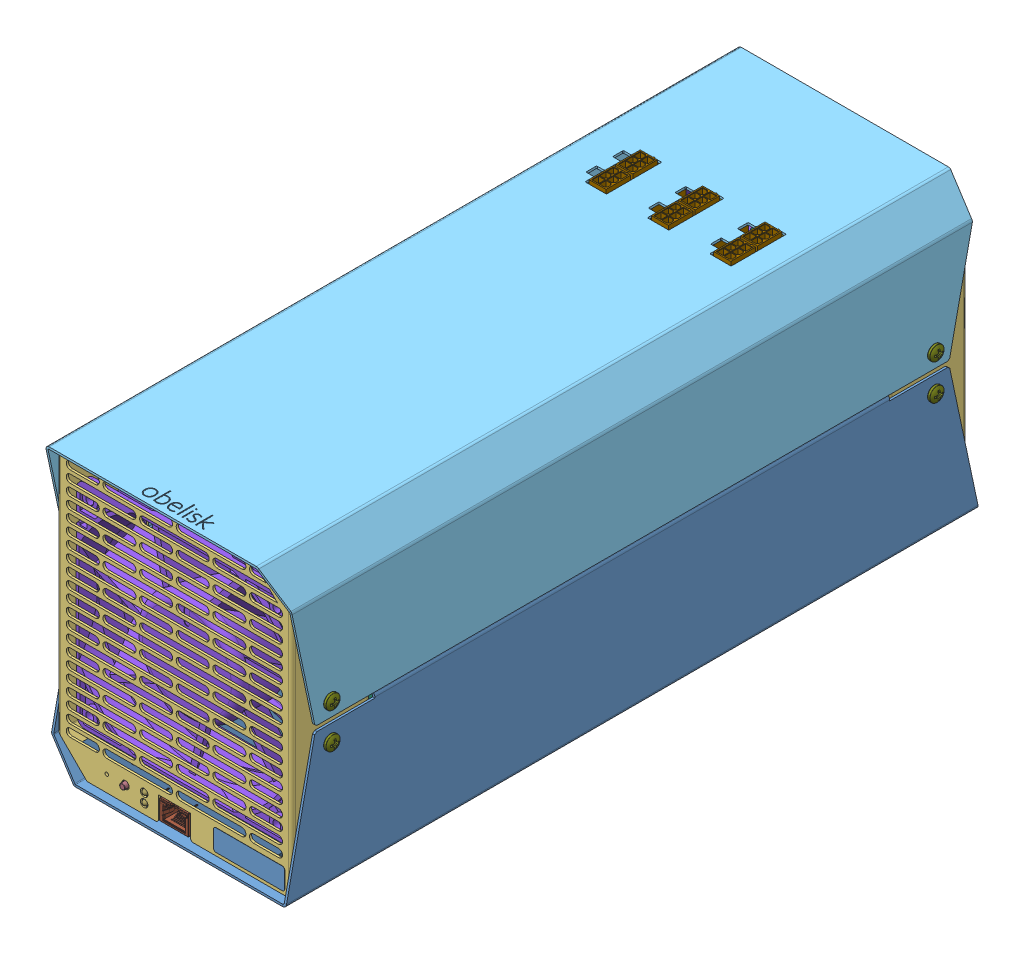
SolidWorks assembly TE-1719_742921-02_SC1-Assem_PRELIM, configuration Captive Nut Fasteners. Lengths in mm.
Overall size (140.99 162.11 388.48).
170 component instances, 20 part files, 45 mates.
Components (placement in the parent):
- TE-1719_SC1-LAYOUT_v03-1: TE-1719_SC1-LAYOUT_v03 [Default] at origin
- TE-1719_742931-04_SC1-Sheet-Metal-Subassem-1: TE-1719_742931-04_SC1-Sheet-Metal-Subassem [Default] at (0 0 5) size (135 156.2 388.48)
  - TE-1719_742923-02_SC1-Base-1: TE-1719_742923-02_SC1-Base [Default] at origin size (135 91 388.48)
    - TE-1719_742923-02_SC1-Base-1: TE-1719_742923-02_SC1-Base [Default] at origin size (135 91 388.48)
    - PEM-Standoff_BSO-440-18ZI-1: PEM-Standoff_BSO-440-18ZI [Default] at (31.1 0.475 -65) x (0 -1 0) z (0 0 1) size (14.27 4.75 5.48)
    - PEM-Standoff_BSO-440-18ZI-2: PEM-Standoff_BSO-440-18ZI [Default] at (31.1 0.475 -249.5) x (0 -1 0) z (0 0 1) size (14.27 4.75 5.48)
    - PEM-Standoff_BSO-440-18ZI-3: PEM-Standoff_BSO-440-18ZI [Default] at (31.1 0.475 -313.5) x (0 -1 0) z (0 0 1) size (14.27 4.75 5.48)
    - PEM-Standoff_BSO-440-18ZI-4: PEM-Standoff_BSO-440-18ZI [Default] at (-3.9 0.475 -313.5) x (0 -1 0) z (0 0 1) size (14.27 4.75 5.48)
    - PEM-Standoff_BSO-440-18ZI-5: PEM-Standoff_BSO-440-18ZI [Default] at (-38.9 0.475 -313.5) x (0 -1 0) z (0 0 1) size (14.27 4.75 5.48)
    - PEM-Standoff_BSO-440-18ZI-6: PEM-Standoff_BSO-440-18ZI [Default] at (-38.9 0.475 -249.5) x (0 -1 0) z (0 0 1) size (14.27 4.75 5.48)
    - PEM-Standoff_BSO-440-18ZI-7: PEM-Standoff_BSO-440-18ZI [Default] at (-3.9 0.475 -249.5) x (0 -1 0) z (0 0 1) size (14.27 4.75 5.48)
    - PEM-Standoff_BSO-440-18ZI-8: PEM-Standoff_BSO-440-18ZI [Default] at (-38.9 0.475 -65) x (0 -1 0) z (0 0 1) size (14.27 4.75 5.48)
  - TE-1719_742926-04_SC1-Front-Grill-1: TE-1719_742926-04_SC1-Front-Grill [Default] at (0 0 -5) size (132 155 55.8)
    - TE-1719_742926-04_742928-04_MASTER-MODEL_SC1-FRONT-REAR-1: TE-1719_742926-04_742928-04_MASTER-MODEL_SC1-FRONT-REAR [Front_PEM-Nuts] at origin size (132 155 55.8)
    - PEM-Nut_S-M4-1ZI-1: PEM-Nut_S-M4-1ZI [Default] at (65.7508 89 -20) x (-1 0 0) z (0 0 -1) size (2.97 7.87 7.87)
    - PEM-Nut_S-M4-1ZI-2: PEM-Nut_S-M4-1ZI [Default] at (65.7508 69 -20) x (-1 0 0) z (0 0 -1) size (2.97 7.87 7.87)
    - PEM-Nut_S-M4-1ZI-3: PEM-Nut_S-M4-1ZI [Default] at (51 1.4492 -20) x (0 1 0) z (-1 0 0) size (2.97 7.87 7.87)
    - PEM-Nut_S-M4-1ZI-8: PEM-Nut_S-M4-1ZI [Default] at (-65.7508 89 -20) size (2.97 7.87 7.87)
    - PEM-Nut_S-M4-1ZI-9: PEM-Nut_S-M4-1ZI [Default] at (-65.7508 69 -20) size (2.97 7.87 7.87)
    - PEM-Nut_S-M4-1ZI-7: PEM-Nut_S-M4-1ZI [Default] at (-35 1.4492 -20) x (0 1 0) z (-1 0 0) size (2.97 7.87 7.87)
  - TE-1719_742928-04_SC1-Rear-Grill-1: TE-1719_742928-04_SC1-Rear-Grill [Default] at (0 0 -384) x (-1 0 0) z (0 0 -1) size (132 155 55.8)
    - TE-1719_742926-04_742928-04_MASTER-MODEL_SC1-FRONT-REAR-1: TE-1719_742926-04_742928-04_MASTER-MODEL_SC1-FRONT-REAR [Rear_PEM-Nuts] at origin size (132 155 55.8)
    - PEM-Nut_S-M4-1ZI-1: PEM-Nut_S-M4-1ZI [Default] at (65.7508 89 -20) x (-1 0 0) z (0 0 -1) size (2.97 7.87 7.87)
    - PEM-Nut_S-M4-1ZI-2: PEM-Nut_S-M4-1ZI [Default] at (65.7508 69 -20) x (-1 0 0) z (0 0 -1) size (2.97 7.87 7.87)
    - PEM-Nut_S-M4-1ZI-3: PEM-Nut_S-M4-1ZI [Default] at (35 1.4492 -20) x (0 1 0) z (-1 0 0) size (2.97 7.87 7.87)
    - PEM-Nut_S-M4-1ZI-9: PEM-Nut_S-M4-1ZI [Default] at (-65.7508 89 -20) size (2.97 7.87 7.87)
    - PEM-Nut_S-M4-1ZI-10: PEM-Nut_S-M4-1ZI [Default] at (-65.7508 69 -20) size (2.97 7.87 7.87)
    - PEM-Nut_S-M4-1ZI-8: PEM-Nut_S-M4-1ZI [Default] at (-51 1.4492 -20) x (0 1 0) z (-1 0 0) size (2.97 7.87 7.87)
  - TE-1719_742924-02_SC1-Cover-1: TE-1719_742924-02_SC1-Cover [Stamped] at origin size (135 77.69 388.48)
  - TE-1719_742933-00_SC1-AIRFLOW-GUIDE-1: TE-1719_742933-00_SC1-AIRFLOW-GUIDE [Default] at (52.5 81 -49.2192) size (53.8 124 20.2)
  - TE-1719_742933-00_SC1-AIRFLOW-GUIDE-2: TE-1719_742933-00_SC1-AIRFLOW-GUIDE [Default] at (52.5 81 -339.7808) x (1 0 0) z (0 0 -1) size (53.8 124 20.2)
- TE-1719_742929-01_SC1-Upper-Guide-1: TE-1719_742929-01_SC1-Upper-Guide [Default] at (0 148 -44.2192) size (114 1.59 21.5)
- FAN_Jaro_JCD1203812LBBA0D(4600)-3: FAN_Jaro_JCD1203812LBBA0D(4600) [Default] at (0 81 -43) x (-1 0 0) z (0 1 0) size (120.5 45.48 120.5)
- SIAHashBd742901R0pcb_03-26-18-1: SIAHashBd742901R0pcb_03-26-18 [Default] at (-31.3 17.4875 -316.5) x (0 0 1) z (-1 0 0) size (258 156.75 30.01)
- PCB_Main-Control-Board_REF-02-1: PCB_Main-Control-Board_REF-02 [Default] at origin size (110 11.6 320)
- M-RJE73-188-00XX0-REVG1-1: M-RJE73-188-00XX0-REVG1 [Default] at (0 8.4625 -10.56) x (-1 0 0) z (0 0 1) size (16.14 13.57 15.3)
- LED_Dual-3mm_Dialight-1: LED_Dual-3mm_Dialight [Default] at (-17 14.2875 -2.2192) x (0 0 -1) z (-1 0 0) size (11 13.64 4.32)
- EVQPF008K-1: EVQPF008K [Default] at (-27.5 10.2875 -4.2192) x (-1 0 0) z (0 0 1) size (8.58 10.9 12.35)
- EVQPF008K-2: EVQPF008K [Default] at (-38 10.2875 -7.7192) x (-1 0 0) z (0 0 1) size (8.58 10.9 12.35)
- SCREW_4-40x250_SEMS-SCREW_90402A106-1: SCREW_4-40x250_SEMS-SCREW_90402A106 [90402A106] at (31.0998 10.1058 -60) x (1 0 0) z (0 1 0) size (5.84 5.84 8.52)
- SCREW_10-14X750_THREAD-FORM_99461A460-1: SCREW_10-14X750_THREAD-FORM_99461A460 [99461A460] at (52.5 133.5 -34.6942) x (-0.923728 -0.383049 0) z (0 0 -1) size (9.47 9.47 23.08)
- SCREW_M4X6_NYLON-PATCH_BLACK_95911A254-26: SCREW_M4X6_NYLON-PATCH_BLACK_95911A254 [95911A254] at (61.5 89 -20) x (0 0 -1) z (-1 0 0) size (8 8 9.2)
- SCREW_M4X6_NYLON-PATCH_BLACK_95911A254-27: SCREW_M4X6_NYLON-PATCH_BLACK_95911A254 [95911A254] at (51 6 -20) x (1 0 0) z (0 1 0) size (8 8 9.2)
- SCREW_M4X6_NYLON-PATCH_BLACK_95911A254-28: SCREW_M4X6_NYLON-PATCH_BLACK_95911A254 [95911A254] at (61.5 69 -20) x (0 0 1) z (-1 0 0) size (8 8 9.2)
- SCREW_M4X6_NYLON-PATCH_BLACK_95911A254-29: SCREW_M4X6_NYLON-PATCH_BLACK_95911A254 [95911A254] at (61.5 69 -359) x (0 0 1) z (-1 0 0) size (8 8 9.2)
- SCREW_M4X6_NYLON-PATCH_BLACK_95911A254-30: SCREW_M4X6_NYLON-PATCH_BLACK_95911A254 [95911A254] at (61.5 89 -359) x (0 0 -1) z (-1 0 0) size (8 8 9.2)
- SCREW_M4X6_NYLON-PATCH_BLACK_95911A254-31: SCREW_M4X6_NYLON-PATCH_BLACK_95911A254 [95911A254] at (-61.5 69 -20) x (0 0 -1) z (1 0 0) size (8 8 9.2)
- SCREW_M4X6_NYLON-PATCH_BLACK_95911A254-32: SCREW_M4X6_NYLON-PATCH_BLACK_95911A254 [95911A254] at (-61.5 89 -20) x (0 0 1) z (1 0 0) size (8 8 9.2)
- SCREW_M4X6_NYLON-PATCH_BLACK_95911A254-33: SCREW_M4X6_NYLON-PATCH_BLACK_95911A254 [95911A254] at (-61.5 69 -359) x (0 0 -1) z (1 0 0) size (8 8 9.2)
- SCREW_M4X6_NYLON-PATCH_BLACK_95911A254-34: SCREW_M4X6_NYLON-PATCH_BLACK_95911A254 [95911A254] at (-61.5 89 -359) x (0 0 1) z (1 0 0) size (8 8 9.2)
- SCREW_10-14X750_THREAD-FORM_99461A460-9: SCREW_10-14X750_THREAD-FORM_99461A460 [99461A460] at (-52.5 133.5 -34.6942) x (0.923728 -0.383049 0) z (0 0 -1) size (9.47 9.47 23.08)
- SCREW_4-40x250_SEMS-SCREW_90402A106-2: SCREW_4-40x250_SEMS-SCREW_90402A106 [90402A106] at (31.0998 10.1058 -244.5) x (1 0 0) z (0 1 0) size (5.84 5.84 8.52)
- SCREW_4-40x250_SEMS-SCREW_90402A106-3: SCREW_4-40x250_SEMS-SCREW_90402A106 [90402A106] at (31.0998 10.1058 -308.5) x (1 0 0) z (0 1 0) size (5.84 5.84 8.52)
- SCREW_4-40x250_SEMS-SCREW_90402A106-4: SCREW_4-40x250_SEMS-SCREW_90402A106 [90402A106] at (-38.9002 10.1058 -60) x (1 0 0) z (0 1 0) size (5.84 5.84 8.52)
- SCREW_4-40x250_SEMS-SCREW_90402A106-5: SCREW_4-40x250_SEMS-SCREW_90402A106 [90402A106] at (-3.9002 10.1058 -244.5) x (1 0 0) z (0 1 0) size (5.84 5.84 8.52)
- SCREW_4-40x250_SEMS-SCREW_90402A106-6: SCREW_4-40x250_SEMS-SCREW_90402A106 [90402A106] at (-38.9002 10.1058 -244.5) x (1 0 0) z (0 1 0) size (5.84 5.84 8.52)
- SCREW_4-40x250_SEMS-SCREW_90402A106-7: SCREW_4-40x250_SEMS-SCREW_90402A106 [90402A106] at (-38.9002 10.1058 -308.5) x (1 0 0) z (0 1 0) size (5.84 5.84 8.52)
- SCREW_4-40x250_SEMS-SCREW_90402A106-8: SCREW_4-40x250_SEMS-SCREW_90402A106 [90402A106] at (-3.9002 10.1058 -308.5) x (1 0 0) z (0 1 0) size (5.84 5.84 8.52)
- SCREW_10-14X750_THREAD-FORM_99461A460-10: SCREW_10-14X750_THREAD-FORM_99461A460 [99461A460] at (52.5 28.5 -34.6942) x (0.923728 -0.383049 0) z (0 0 -1) size (9.47 9.47 23.08)
- SCREW_10-14X750_THREAD-FORM_99461A460-11: SCREW_10-14X750_THREAD-FORM_99461A460 [99461A460] at (-52.5 28.5 -34.6942) x (-0.923728 -0.383049 0) z (0 0 -1) size (9.47 9.47 23.08)
- FAN_Jaro_JCD1203812LBBA0D(4600)-4: FAN_Jaro_JCD1203812LBBA0D(4600) [Default] at (0 81 -375.9987) x (-1 0 0) z (0 1 0) size (120.5 45.48 120.5)
- SCREW_10-14X750_THREAD-FORM_99461A460-12: SCREW_10-14X750_THREAD-FORM_99461A460 [99461A460] at (52.5 133.5 -344.3058) x (0.923728 0.383049 0) z (0 0 1) size (9.47 9.47 23.08)
- SCREW_10-14X750_THREAD-FORM_99461A460-13: SCREW_10-14X750_THREAD-FORM_99461A460 [99461A460] at (-52.5 133.5 -344.3058) x (-0.923728 0.383049 0) z (0 0 1) size (9.47 9.47 23.08)
- SCREW_10-14X750_THREAD-FORM_99461A460-14: SCREW_10-14X750_THREAD-FORM_99461A460 [99461A460] at (52.5 28.5 -344.3058) x (-0.923728 0.383049 0) z (0 0 1) size (9.47 9.47 23.08)
- SCREW_10-14X750_THREAD-FORM_99461A460-15: SCREW_10-14X750_THREAD-FORM_99461A460 [99461A460] at (-52.5 28.5 -344.3058) x (0.923728 0.383049 0) z (0 0 1) size (9.47 9.47 23.08)
- SCREW_M4X6_NYLON-PATCH_BLACK_95911A254-35: SCREW_M4X6_NYLON-PATCH_BLACK_95911A254 [95911A254] at (51 6 -359) x (1 0 0) z (0 1 0) size (8 8 9.2)
- SCREW_M4X6_NYLON-PATCH_BLACK_95911A254-36: SCREW_M4X6_NYLON-PATCH_BLACK_95911A254 [95911A254] at (-35 6 -20) x (-1 0 0) z (0 1 0) size (8 8 9.2)
- SCREW_M4X6_NYLON-PATCH_BLACK_95911A254-37: SCREW_M4X6_NYLON-PATCH_BLACK_95911A254 [95911A254] at (-35 6 -359) x (-1 0 0) z (0 1 0) size (8 8 9.2)
- SIAHashBd742901R0pcb_03-26-18-4: SIAHashBd742901R0pcb_03-26-18 [Default] at (3.7 17.4875 -316.5) x (0 0 1) z (-1 0 0) size (258 156.75 30.01)
- SIAHashBd742901R0pcb_03-26-18-5: SIAHashBd742901R0pcb_03-26-18 [Default] at (38.7 17.4875 -316.5) x (0 0 1) z (-1 0 0) size (258 156.75 30.01)
- TE-1719_742929-01_SC1-Upper-Guide-3: TE-1719_742929-01_SC1-Upper-Guide [Default] at (0 149.5875 -334.7808) x (1 0 0) z (0 0 -1) size (114 1.59 21.5)
- RIVET_3-32_97447A110-1: RIVET_3-32_97447A110 [Default] at (37 149.5875 -50.2192) size (5.03 10.34 5.03)
- RIVET_3-32_97447A110-2: RIVET_3-32_97447A110 [Default] at (37 149.5875 -328.7808) size (5.03 10.34 5.03)
- RIVET_3-32_97447A110-3: RIVET_3-32_97447A110 [Default] at (-37 149.5875 -50.2192) x (-1 0 0) z (0 0 -1) size (5.03 10.34 5.03)
- RIVET_3-32_97447A110-4: RIVET_3-32_97447A110 [Default] at (-37 149.5875 -328.7808) x (-1 0 0) z (0 0 -1) size (5.03 10.34 5.03)
- RIVET-WASHER_3-32_90183A308-1: RIVET-WASHER_3-32_90183A308 [90183A308] at (37 146.7808 -50.2192) x (-0.837169 0 -0.546944) z (0 1 0) size (7.92 7.92 1.73)
- RIVET-WASHER_3-32_90183A308-2: RIVET-WASHER_3-32_90183A308 [90183A308] at (37 145.0536 -328.7808) x (-0.837169 0 0.546944) z (0 -1 0) size (7.92 7.92 1.73)
- RIVET-WASHER_3-32_90183A308-3: RIVET-WASHER_3-32_90183A308 [90183A308] at (-37 145.0536 -50.2192) x (0.837169 0 -0.546944) z (0 -1 0) size (7.92 7.92 1.73)
- RIVET-WASHER_3-32_90183A308-4: RIVET-WASHER_3-32_90183A308 [90183A308] at (-37 146.7808 -328.7808) x (0.837169 0 0.546944) z (0 1 0) size (7.92 7.92 1.73)
- TE-1719_742931-04_SC1-Sheet-Metal-Subassem-2: TE-1719_742931-04_SC1-Sheet-Metal-Subassem [Default] at (150 0 5) size (135 156.2 388.48) (suppressed, hidden)
  - TE-1719_742923-02_SC1-Base-1: TE-1719_742923-02_SC1-Base [Default] at origin size (135 91 388.48)
    - TE-1719_742923-02_SC1-Base-1: TE-1719_742923-02_SC1-Base [Default] at origin size (135 91 388.48)
    - PEM-Standoff_BSO-440-18ZI-1: PEM-Standoff_BSO-440-18ZI [Default] at (31.1 0.475 -65) x (0 -1 0) z (0 0 1) size (14.27 4.75 5.48)
    - PEM-Standoff_BSO-440-18ZI-2: PEM-Standoff_BSO-440-18ZI [Default] at (31.1 0.475 -249.5) x (0 -1 0) z (0 0 1) size (14.27 4.75 5.48)
    - PEM-Standoff_BSO-440-18ZI-3: PEM-Standoff_BSO-440-18ZI [Default] at (31.1 0.475 -313.5) x (0 -1 0) z (0 0 1) size (14.27 4.75 5.48)
    - PEM-Standoff_BSO-440-18ZI-4: PEM-Standoff_BSO-440-18ZI [Default] at (-3.9 0.475 -313.5) x (0 -1 0) z (0 0 1) size (14.27 4.75 5.48)
    - PEM-Standoff_BSO-440-18ZI-5: PEM-Standoff_BSO-440-18ZI [Default] at (-38.9 0.475 -313.5) x (0 -1 0) z (0 0 1) size (14.27 4.75 5.48)
    - PEM-Standoff_BSO-440-18ZI-6: PEM-Standoff_BSO-440-18ZI [Default] at (-38.9 0.475 -249.5) x (0 -1 0) z (0 0 1) size (14.27 4.75 5.48)
    - PEM-Standoff_BSO-440-18ZI-7: PEM-Standoff_BSO-440-18ZI [Default] at (-3.9 0.475 -249.5) x (0 -1 0) z (0 0 1) size (14.27 4.75 5.48)
    - PEM-Standoff_BSO-440-18ZI-8: PEM-Standoff_BSO-440-18ZI [Default] at (-38.9 0.475 -65) x (0 -1 0) z (0 0 1) size (14.27 4.75 5.48)
  - TE-1719_742926-04_SC1-Front-Grill-1: TE-1719_742926-04_SC1-Front-Grill [Default] at (0 0 -5) size (132 155 55.8)
    - TE-1719_742926-04_742928-04_MASTER-MODEL_SC1-FRONT-REAR-1: TE-1719_742926-04_742928-04_MASTER-MODEL_SC1-FRONT-REAR [Front_PEM-Nuts] at origin size (132 155 55.8)
    - PEM-Nut_S-M4-1ZI-1: PEM-Nut_S-M4-1ZI [Default] at (65.7508 89 -20) x (-1 0 0) z (0 0 -1) size (2.97 7.87 7.87)
    - PEM-Nut_S-M4-1ZI-2: PEM-Nut_S-M4-1ZI [Default] at (65.7508 69 -20) x (-1 0 0) z (0 0 -1) size (2.97 7.87 7.87)
    - PEM-Nut_S-M4-1ZI-3: PEM-Nut_S-M4-1ZI [Default] at (51 1.4492 -20) x (0 1 0) z (-1 0 0) size (2.97 7.87 7.87)
    - PEM-Nut_S-M4-1ZI-8: PEM-Nut_S-M4-1ZI [Default] at (-65.7508 89 -20) size (2.97 7.87 7.87)
    - PEM-Nut_S-M4-1ZI-9: PEM-Nut_S-M4-1ZI [Default] at (-65.7508 69 -20) size (2.97 7.87 7.87)
    - PEM-Nut_S-M4-1ZI-7: PEM-Nut_S-M4-1ZI [Default] at (-35 1.4492 -20) x (0 1 0) z (-1 0 0) size (2.97 7.87 7.87)
  - TE-1719_742928-04_SC1-Rear-Grill-1: TE-1719_742928-04_SC1-Rear-Grill [Default] at (0 0 -384) x (-1 0 0) z (0 0 -1) size (132 155 55.8)
    - TE-1719_742926-04_742928-04_MASTER-MODEL_SC1-FRONT-REAR-1: TE-1719_742926-04_742928-04_MASTER-MODEL_SC1-FRONT-REAR [Rear_PEM-Nuts] at origin size (132 155 55.8)
    - PEM-Nut_S-M4-1ZI-1: PEM-Nut_S-M4-1ZI [Default] at (65.7508 89 -20) x (-1 0 0) z (0 0 -1) size (2.97 7.87 7.87)
    - PEM-Nut_S-M4-1ZI-2: PEM-Nut_S-M4-1ZI [Default] at (65.7508 69 -20) x (-1 0 0) z (0 0 -1) size (2.97 7.87 7.87)
    - PEM-Nut_S-M4-1ZI-3: PEM-Nut_S-M4-1ZI [Default] at (35 1.4492 -20) x (0 1 0) z (-1 0 0) size (2.97 7.87 7.87)
    - PEM-Nut_S-M4-1ZI-9: PEM-Nut_S-M4-1ZI [Default] at (-65.7508 89 -20) size (2.97 7.87 7.87)
    - PEM-Nut_S-M4-1ZI-10: PEM-Nut_S-M4-1ZI [Default] at (-65.7508 69 -20) size (2.97 7.87 7.87)
    - PEM-Nut_S-M4-1ZI-8: PEM-Nut_S-M4-1ZI [Default] at (-51 1.4492 -20) x (0 1 0) z (-1 0 0) size (2.97 7.87 7.87)
  - TE-1719_742924-02_SC1-Cover-1: TE-1719_742924-02_SC1-Cover [Stamped] at origin size (135 77.69 388.48)
  - TE-1719_742933-00_SC1-AIRFLOW-GUIDE-1: TE-1719_742933-00_SC1-AIRFLOW-GUIDE [Default] at (52.5 81 -49.2192) size (53.8 124 20.2)
  - TE-1719_742933-00_SC1-AIRFLOW-GUIDE-2: TE-1719_742933-00_SC1-AIRFLOW-GUIDE [Default] at (52.5 81 -339.7808) x (1 0 0) z (0 0 -1) size (53.8 124 20.2)
- TE-1719_742931-04_SC1-Sheet-Metal-Subassem-3: TE-1719_742931-04_SC1-Sheet-Metal-Subassem [Default] at (300 0 5) size (135 156.2 388.48) (suppressed, hidden)
  - TE-1719_742923-02_SC1-Base-1: TE-1719_742923-02_SC1-Base [Default] at origin size (135 91 388.48)
    - TE-1719_742923-02_SC1-Base-1: TE-1719_742923-02_SC1-Base [Default] at origin size (135 91 388.48)
    - PEM-Standoff_BSO-440-18ZI-1: PEM-Standoff_BSO-440-18ZI [Default] at (31.1 0.475 -65) x (0 -1 0) z (0 0 1) size (14.27 4.75 5.48)
    - PEM-Standoff_BSO-440-18ZI-2: PEM-Standoff_BSO-440-18ZI [Default] at (31.1 0.475 -249.5) x (0 -1 0) z (0 0 1) size (14.27 4.75 5.48)
    - PEM-Standoff_BSO-440-18ZI-3: PEM-Standoff_BSO-440-18ZI [Default] at (31.1 0.475 -313.5) x (0 -1 0) z (0 0 1) size (14.27 4.75 5.48)
    - PEM-Standoff_BSO-440-18ZI-4: PEM-Standoff_BSO-440-18ZI [Default] at (-3.9 0.475 -313.5) x (0 -1 0) z (0 0 1) size (14.27 4.75 5.48)
    - PEM-Standoff_BSO-440-18ZI-5: PEM-Standoff_BSO-440-18ZI [Default] at (-38.9 0.475 -313.5) x (0 -1 0) z (0 0 1) size (14.27 4.75 5.48)
    - PEM-Standoff_BSO-440-18ZI-6: PEM-Standoff_BSO-440-18ZI [Default] at (-38.9 0.475 -249.5) x (0 -1 0) z (0 0 1) size (14.27 4.75 5.48)
    - PEM-Standoff_BSO-440-18ZI-7: PEM-Standoff_BSO-440-18ZI [Default] at (-3.9 0.475 -249.5) x (0 -1 0) z (0 0 1) size (14.27 4.75 5.48)
    - PEM-Standoff_BSO-440-18ZI-8: PEM-Standoff_BSO-440-18ZI [Default] at (-38.9 0.475 -65) x (0 -1 0) z (0 0 1) size (14.27 4.75 5.48)
  - TE-1719_742926-04_SC1-Front-Grill-1: TE-1719_742926-04_SC1-Front-Grill [Default] at (0 0 -5) size (132 155 55.8)
    - TE-1719_742926-04_742928-04_MASTER-MODEL_SC1-FRONT-REAR-1: TE-1719_742926-04_742928-04_MASTER-MODEL_SC1-FRONT-REAR [Front_PEM-Nuts] at origin size (132 155 55.8)
    - PEM-Nut_S-M4-1ZI-1: PEM-Nut_S-M4-1ZI [Default] at (65.7508 89 -20) x (-1 0 0) z (0 0 -1) size (2.97 7.87 7.87)
    - PEM-Nut_S-M4-1ZI-2: PEM-Nut_S-M4-1ZI [Default] at (65.7508 69 -20) x (-1 0 0) z (0 0 -1) size (2.97 7.87 7.87)
    - PEM-Nut_S-M4-1ZI-3: PEM-Nut_S-M4-1ZI [Default] at (51 1.4492 -20) x (0 1 0) z (-1 0 0) size (2.97 7.87 7.87)
    - PEM-Nut_S-M4-1ZI-8: PEM-Nut_S-M4-1ZI [Default] at (-65.7508 89 -20) size (2.97 7.87 7.87)
    - PEM-Nut_S-M4-1ZI-9: PEM-Nut_S-M4-1ZI [Default] at (-65.7508 69 -20) size (2.97 7.87 7.87)
    - PEM-Nut_S-M4-1ZI-7: PEM-Nut_S-M4-1ZI [Default] at (-35 1.4492 -20) x (0 1 0) z (-1 0 0) size (2.97 7.87 7.87)
  - TE-1719_742928-04_SC1-Rear-Grill-1: TE-1719_742928-04_SC1-Rear-Grill [Default] at (0 0 -384) x (-1 0 0) z (0 0 -1) size (132 155 55.8)
    - TE-1719_742926-04_742928-04_MASTER-MODEL_SC1-FRONT-REAR-1: TE-1719_742926-04_742928-04_MASTER-MODEL_SC1-FRONT-REAR [Rear_PEM-Nuts] at origin size (132 155 55.8)
    - PEM-Nut_S-M4-1ZI-1: PEM-Nut_S-M4-1ZI [Default] at (65.7508 89 -20) x (-1 0 0) z (0 0 -1) size (2.97 7.87 7.87)
    - PEM-Nut_S-M4-1ZI-2: PEM-Nut_S-M4-1ZI [Default] at (65.7508 69 -20) x (-1 0 0) z (0 0 -1) size (2.97 7.87 7.87)
    - PEM-Nut_S-M4-1ZI-3: PEM-Nut_S-M4-1ZI [Default] at (35 1.4492 -20) x (0 1 0) z (-1 0 0) size (2.97 7.87 7.87)
    - PEM-Nut_S-M4-1ZI-9: PEM-Nut_S-M4-1ZI [Default] at (-65.7508 89 -20) size (2.97 7.87 7.87)
    - PEM-Nut_S-M4-1ZI-10: PEM-Nut_S-M4-1ZI [Default] at (-65.7508 69 -20) size (2.97 7.87 7.87)
    - PEM-Nut_S-M4-1ZI-8: PEM-Nut_S-M4-1ZI [Default] at (-51 1.4492 -20) x (0 1 0) z (-1 0 0) size (2.97 7.87 7.87)
  - TE-1719_742924-02_SC1-Cover-1: TE-1719_742924-02_SC1-Cover [Stamped] at origin size (135 77.69 388.48)
  - TE-1719_742933-00_SC1-AIRFLOW-GUIDE-1: TE-1719_742933-00_SC1-AIRFLOW-GUIDE [Default] at (52.5 81 -49.2192) size (53.8 124 20.2)
  - TE-1719_742933-00_SC1-AIRFLOW-GUIDE-2: TE-1719_742933-00_SC1-AIRFLOW-GUIDE [Default] at (52.5 81 -339.7808) x (1 0 0) z (0 0 -1) size (53.8 124 20.2)
- TE-1719_742931-04_SC1-Sheet-Metal-Subassem-4: TE-1719_742931-04_SC1-Sheet-Metal-Subassem [Default] at (450 0 5) size (135 156.2 388.48) (suppressed, hidden)
  - TE-1719_742923-02_SC1-Base-1: TE-1719_742923-02_SC1-Base [Default] at origin size (135 91 388.48)
    - TE-1719_742923-02_SC1-Base-1: TE-1719_742923-02_SC1-Base [Default] at origin size (135 91 388.48)
    - PEM-Standoff_BSO-440-18ZI-1: PEM-Standoff_BSO-440-18ZI [Default] at (31.1 0.475 -65) x (0 -1 0) z (0 0 1) size (14.27 4.75 5.48)
    - PEM-Standoff_BSO-440-18ZI-2: PEM-Standoff_BSO-440-18ZI [Default] at (31.1 0.475 -249.5) x (0 -1 0) z (0 0 1) size (14.27 4.75 5.48)
    - PEM-Standoff_BSO-440-18ZI-3: PEM-Standoff_BSO-440-18ZI [Default] at (31.1 0.475 -313.5) x (0 -1 0) z (0 0 1) size (14.27 4.75 5.48)
    - PEM-Standoff_BSO-440-18ZI-4: PEM-Standoff_BSO-440-18ZI [Default] at (-3.9 0.475 -313.5) x (0 -1 0) z (0 0 1) size (14.27 4.75 5.48)
    - PEM-Standoff_BSO-440-18ZI-5: PEM-Standoff_BSO-440-18ZI [Default] at (-38.9 0.475 -313.5) x (0 -1 0) z (0 0 1) size (14.27 4.75 5.48)
    - PEM-Standoff_BSO-440-18ZI-6: PEM-Standoff_BSO-440-18ZI [Default] at (-38.9 0.475 -249.5) x (0 -1 0) z (0 0 1) size (14.27 4.75 5.48)
    - PEM-Standoff_BSO-440-18ZI-7: PEM-Standoff_BSO-440-18ZI [Default] at (-3.9 0.475 -249.5) x (0 -1 0) z (0 0 1) size (14.27 4.75 5.48)
    - PEM-Standoff_BSO-440-18ZI-8: PEM-Standoff_BSO-440-18ZI [Default] at (-38.9 0.475 -65) x (0 -1 0) z (0 0 1) size (14.27 4.75 5.48)
  - TE-1719_742926-04_SC1-Front-Grill-1: TE-1719_742926-04_SC1-Front-Grill [Default] at (0 0 -5) size (132 155 55.8)
    - TE-1719_742926-04_742928-04_MASTER-MODEL_SC1-FRONT-REAR-1: TE-1719_742926-04_742928-04_MASTER-MODEL_SC1-FRONT-REAR [Front_PEM-Nuts] at origin size (132 155 55.8)
    - PEM-Nut_S-M4-1ZI-1: PEM-Nut_S-M4-1ZI [Default] at (65.7508 89 -20) x (-1 0 0) z (0 0 -1) size (2.97 7.87 7.87)
    - PEM-Nut_S-M4-1ZI-2: PEM-Nut_S-M4-1ZI [Default] at (65.7508 69 -20) x (-1 0 0) z (0 0 -1) size (2.97 7.87 7.87)
    - PEM-Nut_S-M4-1ZI-3: PEM-Nut_S-M4-1ZI [Default] at (51 1.4492 -20) x (0 1 0) z (-1 0 0) size (2.97 7.87 7.87)
    - PEM-Nut_S-M4-1ZI-8: PEM-Nut_S-M4-1ZI [Default] at (-65.7508 89 -20) size (2.97 7.87 7.87)
    - PEM-Nut_S-M4-1ZI-9: PEM-Nut_S-M4-1ZI [Default] at (-65.7508 69 -20) size (2.97 7.87 7.87)
    - PEM-Nut_S-M4-1ZI-7: PEM-Nut_S-M4-1ZI [Default] at (-35 1.4492 -20) x (0 1 0) z (-1 0 0) size (2.97 7.87 7.87)
  - TE-1719_742928-04_SC1-Rear-Grill-1: TE-1719_742928-04_SC1-Rear-Grill [Default] at (0 0 -384) x (-1 0 0) z (0 0 -1) size (132 155 55.8)
    - TE-1719_742926-04_742928-04_MASTER-MODEL_SC1-FRONT-REAR-1: TE-1719_742926-04_742928-04_MASTER-MODEL_SC1-FRONT-REAR [Rear_PEM-Nuts] at origin size (132 155 55.8)
    - PEM-Nut_S-M4-1ZI-1: PEM-Nut_S-M4-1ZI [Default] at (65.7508 89 -20) x (-1 0 0) z (0 0 -1) size (2.97 7.87 7.87)
    - PEM-Nut_S-M4-1ZI-2: PEM-Nut_S-M4-1ZI [Default] at (65.7508 69 -20) x (-1 0 0) z (0 0 -1) size (2.97 7.87 7.87)
    - PEM-Nut_S-M4-1ZI-3: PEM-Nut_S-M4-1ZI [Default] at (35 1.4492 -20) x (0 1 0) z (-1 0 0) size (2.97 7.87 7.87)
    - PEM-Nut_S-M4-1ZI-9: PEM-Nut_S-M4-1ZI [Default] at (-65.7508 89 -20) size (2.97 7.87 7.87)
    - PEM-Nut_S-M4-1ZI-10: PEM-Nut_S-M4-1ZI [Default] at (-65.7508 69 -20) size (2.97 7.87 7.87)
    - PEM-Nut_S-M4-1ZI-8: PEM-Nut_S-M4-1ZI [Default] at (-51 1.4492 -20) x (0 1 0) z (-1 0 0) size (2.97 7.87 7.87)
  - TE-1719_742924-02_SC1-Cover-1: TE-1719_742924-02_SC1-Cover [Stamped] at origin size (135 77.69 388.48)
  - TE-1719_742933-00_SC1-AIRFLOW-GUIDE-1: TE-1719_742933-00_SC1-AIRFLOW-GUIDE [Default] at (52.5 81 -49.2192) size (53.8 124 20.2)
  - TE-1719_742933-00_SC1-AIRFLOW-GUIDE-2: TE-1719_742933-00_SC1-AIRFLOW-GUIDE [Default] at (52.5 81 -339.7808) x (1 0 0) z (0 0 -1) size (53.8 124 20.2)
- STICKER_FRONT-1: STICKER_FRONT [Default] at (42 3 0) size (40 12 0.1)
Mates (geometry in assembly coordinates):
- Coincident1: coincident anti-aligned: plane of FAN_Jaro_JCD1203812LBBA0D(4600)-3; plane of assembly through (0 0 0) normal (1 0 0)
- Coincident2: coincident: line of TE-1719_SC1-LAYOUT_v03-1 through (0 81 -5) axis (0 0 -1); plane of FAN_Jaro_JCD1203812LBBA0D(4600)-3 through (0 81 -43) normal (0 1 0)
- Coincident3: coincident: point of TE-1719_SC1-LAYOUT_v03-1; plane of FAN_Jaro_JCD1203812LBBA0D(4600)-3
- Coincident43: coincident: line of TE-1719_SC1-LAYOUT_v03-1 through (0 14.2875 -2.5) axis (0 0 -1); plane of M-RJE73-188-00XX0-REVG1-1 through (7.82 14.2875 -2.8) normal (0 1 0)
- Coincident10: coincident anti-aligned: plane of M-RJE73-188-00XX0-REVG1-1; plane of assembly through (0 0 0) normal (1 0 0)
- Coincident20: coincident: point of TE-1719_SC1-LAYOUT_v03-1; plane of LED_Dual-3mm_Dialight-1 through (-17 14.2875 -2.2192) normal (-1 0 0)
- Coincident61: coincident: line of TE-1719_SC1-LAYOUT_v03-1 through (0 14.2875 -2.5) axis (0 0 -1); plane of LED_Dual-3mm_Dialight-1
- Concentric5: concentric anti-aligned: circle of TE-1719_SC1-LAYOUT_v03-1; cylinder of SCREW_M4X6_NYLON-PATCH_BLACK_95911A254-26 through (70.6 89 -20) axis (-1 0 0) radius 4
- Concentric6: concentric aligned: circle of TE-1719_SC1-LAYOUT_v03-1; cylinder of SCREW_10-14X750_THREAD-FORM_99461A460-1 through (52.5 133.5 -47.5974) axis (0 0 1) radius 4.7371
- Coincident50: coincident: line of TE-1719_SC1-LAYOUT_v03-1 through (0 14.2875 -2.5) axis (0 0 -1); plane of EVQPF008K-1 through (-31.25 14.2875 -5.9692) normal (0 1 0)
- Coincident51: coincident: line of TE-1719_SC1-LAYOUT_v03-1 through (10.2875 -27.5 10.2875) axis (0 0 -1); plane of EVQPF008K-1
- Coincident54: coincident aligned: plane of EVQPF008K-1; plane of EVQPF008K-2
- Coincident55: coincident: point of TE-1719_SC1-LAYOUT_v03-1; plane of EVQPF008K-2
- Concentric11: concentric aligned: cylinder of M-RJE73-188-00XX0-REVG1-1 through (5.74 15.3875 -8.5) axis (0 -1 0) radius 0.8; cylinder of PCB_Main-Control-Board_REF-02-1 through (5.74 15.8875 -8.5) axis (0 -1 0) radius 0.9
- Coincident62: coincident anti-aligned: plane of LED_Dual-3mm_Dialight-1 through (-14.714 14.2875 -2.2192) normal (0 1 0); plane of PCB_Main-Control-Board_REF-02-1 through (0 14.2875 0) normal (0 -1 0)
- Concentric12: concentric: point of TE-1719_SC1-LAYOUT_v03-1; cylinder of SCREW_4-40x250_SEMS-SCREW_90402A106-1 through (31.0998 10.1058 -60) axis (0 -1 0) radius 2.7813
- Parallel4: parallel aligned: plane of SCREW_4-40x250_SEMS-SCREW_90402A106-1; plane of assembly through (0 0 0) normal (1 0 0)
- Coincident74: coincident: line of TE-1719_SC1-LAYOUT_v03-1 through (0 17.4875 -60.5) axis (0 0 -1); plane of SIAHashBd742901R0pcb_03-26-18-1
- Coincident75: coincident: line of TE-1719_SC1-LAYOUT_v03-1 through (0 155.4875 -318.5) axis (0 -1 0); plane of SIAHashBd742901R0pcb_03-26-18-1 through (-31.2999 155.4875 -318.5) normal (0 0 -1)
- Coincident76: coincident: line of TE-1719_SC1-LAYOUT_v03-1 through (-31.3 0 -318.5) axis (0 0 1); plane of SIAHashBd742901R0pcb_03-26-18-1 through (-31.3 17.4875 -316.5) normal (-1 0 0)
- Distance9: distance = 0 mm aligned: plane of TE-1719_SC1-LAYOUT_v03-1 through (0 0 0) normal (1 0 0); plane of TE-1719_742929-01_SC1-Upper-Guide-1 through (0 148 -44.2192) normal (1 0 0)
- Parallel7: parallel aligned: plane of SIAHashBd742901R0pcb_03-26-18-1; plane of assembly through (0 0 0) normal (0 1 0)
- Coincident84: coincident anti-aligned: plane of PCB_Main-Control-Board_REF-02-1 through (0 15.8875 0) normal (0 1 0); plane of SCREW_4-40x250_SEMS-SCREW_90402A106-1 through (31.0998 15.8875 -60) normal (0 -1 0)
- Parallel9: parallel anti-aligned: plane of SCREW_M4X6_NYLON-PATCH_BLACK_95911A254-26; plane of assembly through (0 0 0) normal (0 1 0)
- Coincident86: coincident aligned: plane of SCREW_M4X6_NYLON-PATCH_BLACK_95911A254-27 through (51 0 -20) normal (0 1 0); plane of assembly through (0 0 0) normal (0 1 0)
- Concentric13: concentric: cylinder of SCREW_M4X6_NYLON-PATCH_BLACK_95911A254-27 through (51 -3.1 -20) axis (0 1 0) radius 4; point of TE-1719_SC1-LAYOUT_v03-1
- Parallel10: parallel aligned: plane of SCREW_M4X6_NYLON-PATCH_BLACK_95911A254-27; plane of assembly through (0 0 0) normal (1 0 0)
- Coincident87: coincident: point of TE-1719_742929-01_SC1-Upper-Guide-1; line of RIVET_3-32_97447A110-1 through (37 136.3662 -50.2192) axis (0 1 0)
- Coincident88: coincident aligned: plane of TE-1719_742929-01_SC1-Upper-Guide-1 through (0 149.5875 -44.2192) normal (0 1 0); plane of RIVET_3-32_97447A110-1 through (37 149.5875 -50.2192) normal (0 1 0)
- Parallel11: parallel aligned: plane of RIVET_3-32_97447A110-1 through (37 149.5875 -50.2192) normal (1 0 0); plane of assembly through (0 0 0) normal (1 0 0)
- Concentric14: concentric aligned: cylinder of RIVET-WASHER_3-32_90183A308-1 through (37 145.0536 -50.2192) axis (0 1 0) radius 3.9624; circle of TE-1719_742929-01_SC1-Upper-Guide-1
- Coincident92: coincident aligned: plane of ? through (0 0 5) normal (0 1 0); plane of assembly through (0 0 0) normal (0 1 0)
- Coincident94: coincident aligned: plane of ? through (0 0 5) normal (1 0 0); plane of assembly through (0 0 0) normal (1 0 0)
- Coincident95: coincident aligned: line of TE-1719_SC1-LAYOUT_v03-1 through (0 158 -189.5) axis (0 -1 0); line of ? through (0 158 -189.5) axis (0 -1 0)
- Distance10: distance = 2.2192 mm anti-aligned: plane of LED_Dual-3mm_Dialight-1; plane of assembly through (0 0 0) normal (0 0 1)
- Distance12: distance = 1.7192 mm aligned: plane of EVQPF008K-1 through (-27.5 10.2875 -4.2192) normal (0 0 1); plane of PCB_Main-Control-Board_REF-02-1 through (-55 15.8875 -2.5) normal (0 0 1)
- Distance13: distance = 5.2192 mm aligned: plane of EVQPF008K-2 through (-38 10.2875 -7.7192) normal (0 0 1); plane of PCB_Main-Control-Board_REF-02-1 through (-55 15.8875 -2.5) normal (0 0 1)
- Coincident100: coincident anti-aligned: plane of TE-1719_742931-04_SC1-Sheet-Metal-Subassem-1/TE-1719_742926-04_SC1-Front-Grill-1/TE-1719_742926-04_742928-04_MASTER-MODEL_SC1-FRONT-REAR-1 through (0 0 -44.2192) normal (0 0 -1); plane of SCREW_10-14X750_THREAD-FORM_99461A460-1 through (52.5 133.5 -44.2192) normal (0 0 1)
- Coincident101: coincident: line of TE-1719_SC1-LAYOUT_v03-1 through (158 67.5 0) axis (0 0 1); plane of SCREW_M4X6_NYLON-PATCH_BLACK_95911A254-26 through (67.5 89 -20) normal (-1 0 0)
- Coincident102: coincident anti-aligned: plane of TE-1719_742931-04_SC1-Sheet-Metal-Subassem-1/TE-1719_742926-04_SC1-Front-Grill-1/TE-1719_742926-04_742928-04_MASTER-MODEL_SC1-FRONT-REAR-1 through (0 0 -44.2192) normal (0 0 -1); plane of TE-1719_742929-01_SC1-Upper-Guide-1 through (-60 149.5875 -44.2192) normal (0 0 1)
- Coincident103: coincident anti-aligned: plane of TE-1719_742931-04_SC1-Sheet-Metal-Subassem-1/TE-1719_742926-04_SC1-Front-Grill-1/TE-1719_742926-04_742928-04_MASTER-MODEL_SC1-FRONT-REAR-1 through (0 148 0) normal (0 1 0); plane of TE-1719_742929-01_SC1-Upper-Guide-1 through (0 148 -44.2192) normal (0 -1 0)
- Coincident104: coincident anti-aligned: plane of TE-1719_742931-04_SC1-Sheet-Metal-Subassem-1/TE-1719_742926-04_SC1-Front-Grill-1/TE-1719_742926-04_742928-04_MASTER-MODEL_SC1-FRONT-REAR-1 through (0 146.7808 0) normal (0 -1 0); plane of RIVET-WASHER_3-32_90183A308-1 through (37 146.7808 -50.2192) normal (0 1 0)
- Distance17: distance = 3 mm aligned: plane of STICKER_FRONT-1 through (42 3 0) normal (0 1 0); plane of assembly through (0 0 0) normal (0 1 0)
- Distance18: distance = 42 mm aligned: plane of STICKER_FRONT-1 through (42 3 0) normal (1 0 0); plane of assembly through (0 0 0) normal (1 0 0)
- Coincident109: coincident aligned: plane of TE-1719_742931-04_SC1-Sheet-Metal-Subassem-1/TE-1719_742926-04_SC1-Front-Grill-1/TE-1719_742926-04_742928-04_MASTER-MODEL_SC1-FRONT-REAR-1 through (0 0 0) normal (0 0 1); plane of STICKER_FRONT-1 through (42 3 0) normal (0 0 1)
